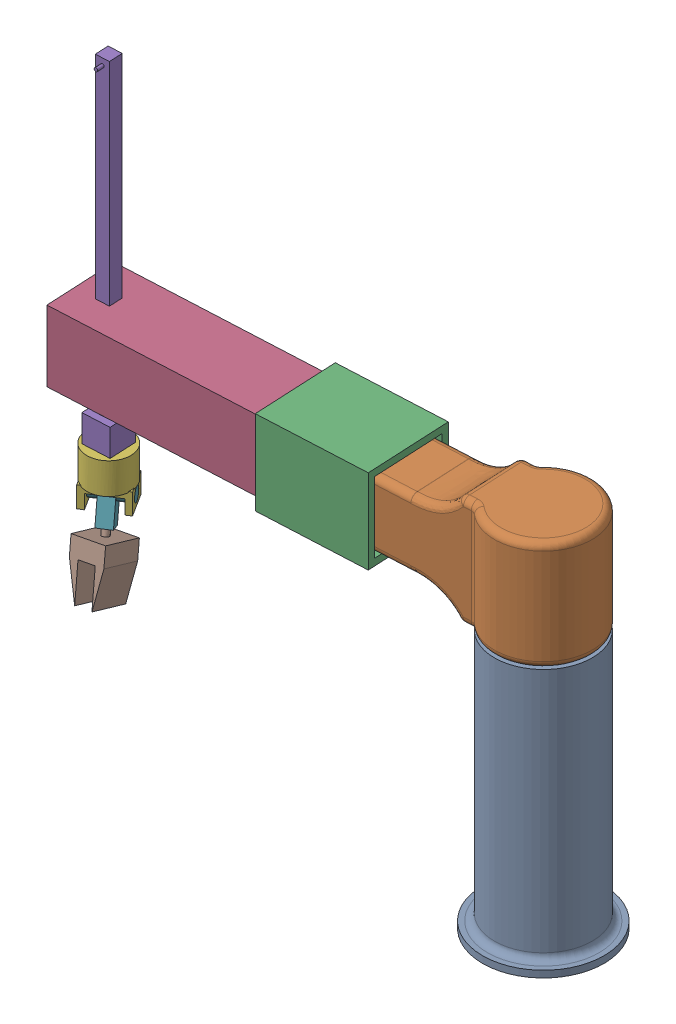
SolidWorks assembly Assem1, configuration Default. Lengths in mm.
Overall size (749.24 831.82 184.68).
7 component instances, 7 part files, 12 mates.
Components (placement in the parent):
- JayRPPBase-1: JayRPPBase [Default] at (685.9932 606.079 1289.2915) size (180 424 180)
- JayRPPRotation-1: JayRPPRotation [Default] at (685.9932 990.079 1289.2915) x (-0.998787 0 0.04923) z (-0.04923 0 -0.998787) size (464.5 166.03 145)
- JayRPPPrismatic1-2: JayRPPPrismatic1 [Default] at (335.2742 1071.079 1306.5782) x (-0.998787 0 0.04923) z (0.04923 0 0.998787) size (464 125 125)
- JayRPPPrismatic2-1: JayRPPPrismatic2 [Default] at (71.5943 937.8951 1319.5748) x (0.998787 0 -0.04923) z (0.04923 0 0.998787) size (40 540 40)
- jaywrist1-1: jaywrist1 [Default] at (71.5943 891.8951 1319.5748) x (-0.535023 0 -0.844837) z (0.844837 0 -0.535023) size (65 75.53 65)
- jaywrist2-1: jaywrist2 [Default] at (71.5943 877.1321 1319.5748) x (0.507701 0.315479 0.801694) z (0.844837 0 -0.535023) size (20 50 60)
- EndEffector-1: EndEffector [Default] at (67.2711 759.966 1378.6566) x (0.985382 0.168788 -0.023083) z (-0.023083 0.266528 0.963551) size (50.8 96.2 50.8)
Mates (geometry in assembly coordinates):
- Coincident2: coincident anti-aligned: plane of JayRPPBase-1 through (685.9932 1030.079 1289.2915) normal (0 1 0); plane of JayRPPRotation-1 through (685.9932 1030.079 1289.2915) normal (0 -1 0)
- Concentric1: concentric aligned: cylinder of JayRPPBase-1 through (685.9932 1030.079 1289.2915) axis (0 -1 0) radius 10; cylinder of JayRPPRotation-1 through (685.9932 1030.079 1289.2915) axis (0 -1 0) radius 10
- Coincident3: coincident anti-aligned: plane of JayRPPRotation-1 through (446.7765 1081.079 1311.0945) normal (-0.04923 0 -0.998787); plane of JayRPPPrismatic1-2 through (487.5822 1061.079 1309.0832) normal (0.04923 0 0.998787)
- Coincident4: coincident anti-aligned: plane of JayRPPRotation-1 through (445.7919 1081.079 1291.1187) normal (0 -1 0); plane of JayRPPPrismatic1-2 through (486.5976 1081.079 1289.1075) normal (0 1 0)
- Coincident5: coincident anti-aligned: plane of JayRPPPrismatic1-2 through (62.0987 963.579 1330.055) normal (0.998787 0 -0.04923); plane of JayRPPPrismatic2-1 through (61.1141 1437.8951 1310.0792) normal (-0.998787 0 0.04923)
- Coincident6: coincident anti-aligned: plane of JayRPPPrismatic1-2 through (81.0898 963.579 1309.0947) normal (0.04923 0 0.998787); plane of JayRPPPrismatic2-1 through (61.1141 1437.8951 1310.0792) normal (-0.04923 0 -0.998787)
- Coincident7: coincident anti-aligned: plane of JayRPPPrismatic2-1 through (71.5943 897.8951 1319.5748) normal (0 -1 0); plane of jaywrist1-1 through (71.5943 897.8951 1319.5748) normal (0 1 0)
- Concentric2: concentric aligned: cylinder of JayRPPPrismatic2-1 through (71.5943 897.8951 1319.5748) axis (0 1 0) radius 10; cylinder of jaywrist1-1 through (71.5943 897.8951 1319.5748) axis (0 1 0) radius 10
- Coincident8: coincident anti-aligned: circle of jaywrist1-1; plane of jaywrist2-1 through (46.2491 877.1321 1335.6255) normal (-0.844837 0 0.535023)
- Concentric3: concentric anti-aligned: cylinder of jaywrist1-1 through (36.1111 877.1321 1342.0458) axis (0.844837 0 -0.535023) radius 10; cylinder of jaywrist2-1 through (96.9394 877.1321 1303.5241) axis (-0.844837 0 0.535023) radius 10
- Coincident9: coincident anti-aligned: plane of jaywrist2-1 through (76.6579 848.6641 1327.5707) normal (0.168788 -0.948933 0.266528); plane of EndEffector-1 through (76.6579 848.6641 1327.5707) normal (-0.168788 0.948933 -0.266528)
- Concentric4: concentric aligned: cylinder of jaywrist2-1 through (76.6579 848.6641 1327.5707) axis (0.168788 -0.948933 0.266528) radius 5; cylinder of EndEffector-1 through (76.6579 848.6641 1327.5707) axis (0.168788 -0.948933 0.266528) radius 5
